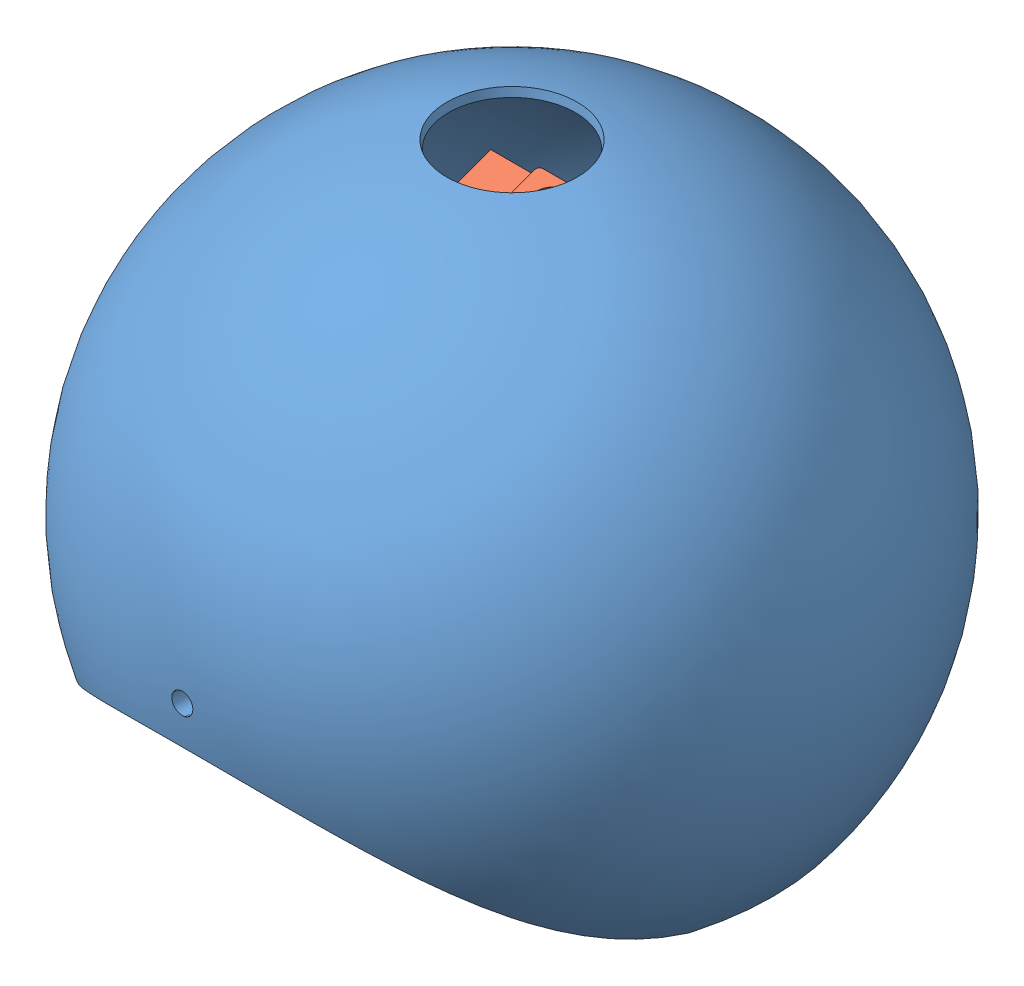
SolidWorks assembly Eyeball+camera, configuration Default. Lengths in mm.
Overall size (156 129.14 156).
2 component instances, 2 part files, 0 mates.
Components (placement in the parent):
- Eye-1: Eye [Default] at (35.3129 80.4307 132.5016) size (156 129.14 156)
- pixy-1: pixy [Default] at (34.5109 129.7856 133.7187) x (1 0 0) z (0 -0.34202 0.939693) size (38.55 5.3 42.4)
